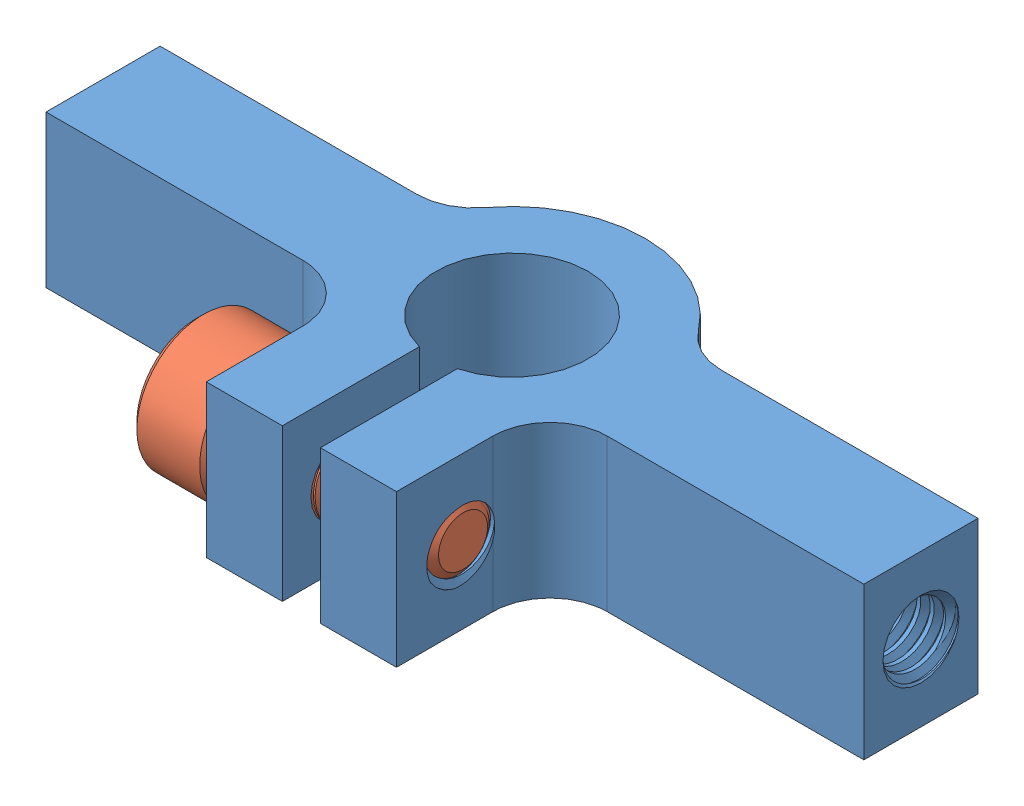
SolidWorks assembly 2-Side, 1-Post Clamping Mount (43mm Width, 8mm Bore) 1402-0043-0008, configuration Default. Lengths in mm.
Overall size (43.01 8 18.07).
2 component instances, 2 part files, 0 mates.
Components (placement in the parent):
- 1402-0043-0008 without hardware.step-1: 1402-0043-0008 without hardware.step [Default] at (-8.8017 -1.8918 -3.2516) size (43.01 8 18.07)
- 2800-0004-0010.step-1: 2800-0004-0010.step [Default] at (-3.8017 -5.8918 4.3214) x (0 0 1) z (0 -1 0) size (7 14.01 7)
